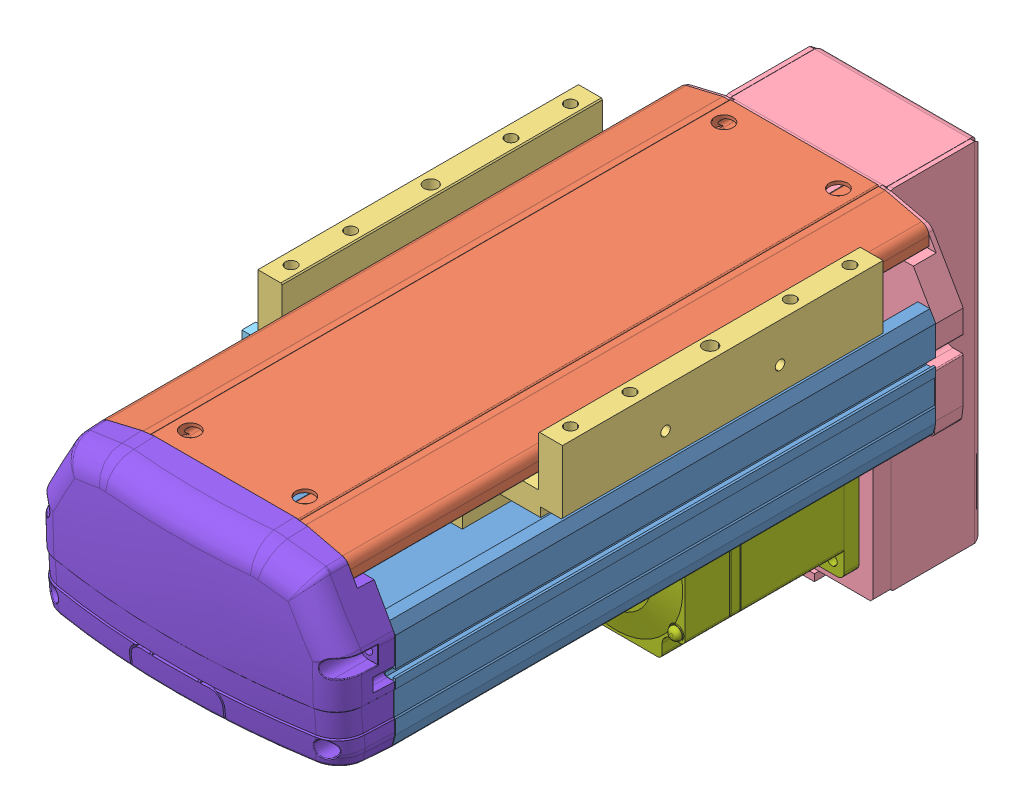
SolidWorks assembly S14-BM-200W, configuration 默认. Lengths in mm.
Overall size (152.61 160.5 347.76).
11 component instances, 9 part files, 34 mates.
Components (placement in the parent):
- S14-BM底座^S14-BM-200W-1: S14-BM底座^S14-BM-200W [默认] at origin size (135 48.03 259) (virtual)
- S14-BM上盖^S14-BM-200W-1: S14-BM上盖^S14-BM-200W [默认] at (0 61 -10) size (109 12.5 253) (virtual)
- S14-B-SFSR16滑座^S14-BM-200W-1: S14-B-SFSR16滑座^S14-BM-200W [默认] at (-1.39 35.7784 72) size (133 62 140) (virtual)
- 复件 S13-14-BM电机板罩壳^S14-BM-200W-1: 复件 S13-14-BM电机板罩壳^S14-BM-200W [默认] at (34.6396 0 343.3649) x (-0.923728 0 0.383049) z (0 -1 0) size (129.3 86.61 155.28) (virtual)
- 复件 光电开关EE-SX672^S14-BM-200W-1: 复件 光电开关EE-SX672^S14-BM-200W [默认] at (-67.5 19.7 76) x (0 0 1) z (-1 0 0) size (26 25 13) (virtual)
- 复件 外置感应片ST14-17^S14-BM-200W-1: 复件 外置感应片ST14-17^S14-BM-200W [默认] at (-67.4964 55 92) x (0 0 1) z (-1 0 0) size (70 30.4 7.7) (virtual)
- 复件 光电开关EE-SX672^S14-BM-200W-2: 复件 光电开关EE-SX672^S14-BM-200W [默认] at (-67.5 19.7 102) x (0 0 1) z (-1 0 0) size (26 25 13) (virtual)
- 复件 光电开关EE-SX672^S14-BM-200W-3: 复件 光电开关EE-SX672^S14-BM-200W [默认] at (-67.5 19.7 149) x (0 0 1) z (-1 0 0) size (26 25 13) (virtual)
- 复件 复件 (2) MSMD022P1AA_200W^S14-BM-200W-1: 复件 复件 (2) MSMD022P1AA_200W^S14-BM-200W [默认] at (0 -41.1 -4) x (0 0 -1) z (0 1 0) size (109 60 60) (virtual)
- YK260EC86E1-KZ01^S14-BM-200W-1: YK260EC86E1-KZ01^S14-BM-200W [默认] at (0 -41.1 7) x (0 1 0) z (0 0 -1) size (60.18 72.76 137.14) (hidden, virtual)
- 复件 (2) 13-14塑胶端盖^S14-BM-200W-1: 复件 (2) 13-14塑胶端盖^S14-BM-200W [Default] at (0 1 256) x (-1 0 0) z (0 0 -1) size (134.5 73.26 30.08) (virtual)
Mates (geometry in assembly coordinates):
- 距离10: distance = 73.5 mm: plane of S14-BM上盖^S14-BM-200W-1 through (-32 73.5 243) normal (0 1 0); plane of S14-BM底座^S14-BM-200W-1 through (-65.3077 0 259) normal (0 -1 0)
- 距离17: distance = 1.39 mm: plane of S14-B-SFSR16滑座^S14-BM-200W-1 through (-1.39 35.7784 72) normal (1 0 0); plane of S14-BM底座^S14-BM-200W-1 through (0 0 0) normal (1 0 0)
- 重合155: coincident: plane of S14-BM底座^S14-BM-200W-1 through (0 0 0) normal (1 0 0); plane of S14-BM上盖^S14-BM-200W-1 through (0 61 -10) normal (1 0 0)
- 距离12: distance = 78 mm: plane of S14-B-SFSR16滑座^S14-BM-200W-1 through (66.5036 78 22) normal (0 1 0); plane of S14-BM底座^S14-BM-200W-1 through (-65.3077 0 259) normal (0 -1 0)
- 重合167: coincident: plane of S14-BM底座^S14-BM-200W-1 through (0 0 0) normal (0 0 1); plane of assembly through (0 0 0) normal (0 0 1)
- 重合168: coincident: plane of S14-BM底座^S14-BM-200W-1 through (0 0 0) normal (0 1 0); plane of assembly through (0 0 0) normal (0 1 0)
- 重合169: coincident: plane of S14-BM底座^S14-BM-200W-1 through (0 0 0) normal (1 0 0); plane of assembly through (0 0 0) normal (1 0 0)
- 宽度1: width: plane of S14-BM底座^S14-BM-200W-1 through (67.5 12 259) normal (1 0 0); plane of S14-BM底座^S14-BM-200W-1 through (-67.5 12 259) normal (-1 0 0); plane of 复件 S13-14-BM电机板罩壳^S14-BM-200W-1 through (-67.5 6.7616 -12) normal (-1 0 0); plane of 复件 S13-14-BM电机板罩壳^S14-BM-200W-1 through (67.5 6.7616 -12) normal (1 0 0)
- 重合172: coincident: plane of S14-BM底座^S14-BM-200W-1 through (-56.75 26.5 0) normal (0 0 -1); plane of 复件 S13-14-BM电机板罩壳^S14-BM-200W-1 through (-64.2481 2 0) normal (0 0 1)
- 距离18: distance = 79.5 mm: plane of S14-BM底座^S14-BM-200W-1 through (31 0 259) normal (0 -1 0); plane of 复件 S13-14-BM电机板罩壳^S14-BM-200W-1 through (0 -79.5 0) normal (0 -1 0)
- 重合174: coincident: plane of YK260EC86E1-KZ01^S14-BM-200W-1 through (27 -14.1 -4) normal (0 0 -1); plane of 复件 S13-14-BM电机板罩壳^S14-BM-200W-1 through (0 1.7 -4) normal (0 0 1)
- 宽度2: width: plane of 复件 S13-14-BM电机板罩壳^S14-BM-200W-1 through (25 -38.1 0) normal (-1 0 0); plane of 复件 S13-14-BM电机板罩壳^S14-BM-200W-1 through (-25 -38.1 0) normal (1 0 0); cylinder of YK260EC86E1-KZ01^S14-BM-200W-1 through (0 -41.1 -34) axis (0 0 1) radius 4
- 距离19: distance = 30 mm: moEndPointRef_w of 复件 S13-14-BM电机板罩壳^S14-BM-200W-1; plane of YK260EC86E1-KZ01^S14-BM-200W-1 through (27 -71.1 -4) normal (0 -1 0)
- 同心78: concentric: cylinder of S14-B-SFSR16滑座^S14-BM-200W-1 through (-66.9964 61 67) axis (-1 0 0) radius 2.1; cylinder of 复件 外置感应片ST14-17^S14-BM-200W-1 through (-67.4964 61 67) axis (-1 0 0) radius 2.55
- 同心79: concentric: cylinder of S14-B-SFSR16滑座^S14-BM-200W-1 through (-66.9964 61 117) axis (-1 0 0) radius 2.1; cylinder of 复件 外置感应片ST14-17^S14-BM-200W-1 through (-67.4964 61 117) axis (-1 0 0) radius 2.55
- 重合176: coincident: plane of S14-B-SFSR16滑座^S14-BM-200W-1 through (-66.4964 16 180.2534) normal (-1 0 0); plane of 复件 外置感应片ST14-17^S14-BM-200W-1 through (-66.4964 55 92) normal (1 0 0)
- 重合177: coincident: plane of S14-BM底座^S14-BM-200W-1 through (-67.5 43.67 259) normal (-1 0 0); plane of 复件 光电开关EE-SX672^S14-BM-200W-1 through (-67.5 44.7 76) normal (1 0 0)
- 距离20: distance = 19.7 mm: plane of S14-BM底座^S14-BM-200W-1 through (-65.3077 0 259) normal (0 -1 0); plane of 复件 光电开关EE-SX672^S14-BM-200W-1 through (-80.5 19.7 76) normal (0 -1 0)
- 重合179: coincident: circle of S14-BM上盖^S14-BM-200W-1; plane of 复件 S13-14-BM电机板罩壳^S14-BM-200W-1 through (0 1.7 -10) normal (0 0 1)
- 距离21: distance = 76 mm: plane of S14-BM底座^S14-BM-200W-1 through (-56.75 26.5 0) normal (0 0 -1); plane of 复件 光电开关EE-SX672^S14-BM-200W-1 through (-80.5 19.7 76) normal (0 0 -1)
- 重合183: coincident: plane of 复件 光电开关EE-SX672^S14-BM-200W-1 through (-80.5 44.7 76) normal (-1 0 0); plane of 复件 光电开关EE-SX672^S14-BM-200W-2 through (-80.5 44.7 102) normal (-1 0 0)
- 重合184: coincident: plane of 复件 光电开关EE-SX672^S14-BM-200W-1 through (-70 32.7 92) normal (0 0 1); plane of 复件 光电开关EE-SX672^S14-BM-200W-2 through (-70 32.7 92) normal (0 0 -1)
- 重合185: coincident: plane of 复件 光电开关EE-SX672^S14-BM-200W-1 through (-80.5 19.7 76) normal (0 -1 0); plane of 复件 光电开关EE-SX672^S14-BM-200W-2 through (-80.5 19.7 102) normal (0 -1 0)
- 重合186: coincident: plane of S14-BM底座^S14-BM-200W-1 through (-67.5 43.67 259) normal (-1 0 0); plane of 复件 光电开关EE-SX672^S14-BM-200W-3 through (-67.5 44.7 149) normal (1 0 0)
- 重合187: coincident: plane of 复件 光电开关EE-SX672^S14-BM-200W-2 through (-80.5 19.7 102) normal (0 -1 0); plane of 复件 光电开关EE-SX672^S14-BM-200W-3 through (-80.5 19.7 149) normal (0 -1 0)
- 距离22: distance = 81 mm: plane of 复件 光电开关EE-SX672^S14-BM-200W-3 through (-80.5 19.7 155) normal (0 0 1); plane of S14-BM底座^S14-BM-200W-1 through (-100.8342 -10 236) normal (0 0 1)
- 宽度3: width: plane of 复件 外置感应片ST14-17^S14-BM-200W-1 through (-74.1964 37.6 84.5) normal (0 0 -1); plane of 复件 外置感应片ST14-17^S14-BM-200W-1 through (-74.1964 53 99.5) normal (0 0 1); plane of 复件 光电开关EE-SX672^S14-BM-200W-1 through (-80.5 19.7 82) normal (0 0 1); plane of 复件 光电开关EE-SX672^S14-BM-200W-2 through (-80.5 19.7 102) normal (0 0 -1)
- 同心80: concentric: cylinder of S14-BM底座^S14-BM-200W-1 through (62.5 39.5 259) axis (0 0 -1) radius 1.4777; cylinder of 复件 (2) 13-14塑胶端盖^S14-BM-200W-1 through (62.5 39.5 236) axis (0 0 -1) radius 2.1
- 宽度4: width: plane of 复件 (2) 13-14塑胶端盖^S14-BM-200W-1 through (67.25 46.7626 236) normal (0.999048 0 0.043619); plane of 复件 (2) 13-14塑胶端盖^S14-BM-200W-1 through (-67.25 2.8914 236) normal (-0.999048 0 0.043619); plane of S14-BM底座^S14-BM-200W-1 through (67.5 12 259) normal (1 0 0); plane of S14-BM底座^S14-BM-200W-1 through (-67.5 12 259) normal (-1 0 0)
- 重合189: coincident: plane of S14-BM底座^S14-BM-200W-1 through (-100.8342 -10 236) normal (0 0 1); plane of 复件 (2) 13-14塑胶端盖^S14-BM-200W-1 through (0 1 236) normal (0 0 -1)
- 宽度5: width: plane of 复件 S13-14-BM电机板罩壳^S14-BM-200W-1 through (25 -38.1 0) normal (-1 0 0); plane of 复件 S13-14-BM电机板罩壳^S14-BM-200W-1 through (-25 -38.1 0) normal (1 0 0); cylinder of 复件 复件 (2) MSMD022P1AA_200W^S14-BM-200W-1 through (0 -41.1 -18.75) axis (0 0 -1) radius 5.5
- 重合190: coincident: plane of 复件 S13-14-BM电机板罩壳^S14-BM-200W-1 through (0 1.7 -4) normal (0 0 1); plane of 复件 复件 (2) MSMD022P1AA_200W^S14-BM-200W-1 through (0 -41.1 -4) normal (0 0 -1)
- 距离23: distance = 30 mm: moEndPointRef_w of 复件 S13-14-BM电机板罩壳^S14-BM-200W-1; plane of 复件 复件 (2) MSMD022P1AA_200W^S14-BM-200W-1 through (-27 -71.1 2.5) normal (0 -1 0)
- 平行1: parallel: plane of 复件 S13-14-BM电机板罩壳^S14-BM-200W-1 through (-36 -79.5 -12) normal (-1 0 0); plane of 复件 复件 (2) MSMD022P1AA_200W^S14-BM-200W-1 through (-30 -14.1 2.5) normal (-1 0 0)
